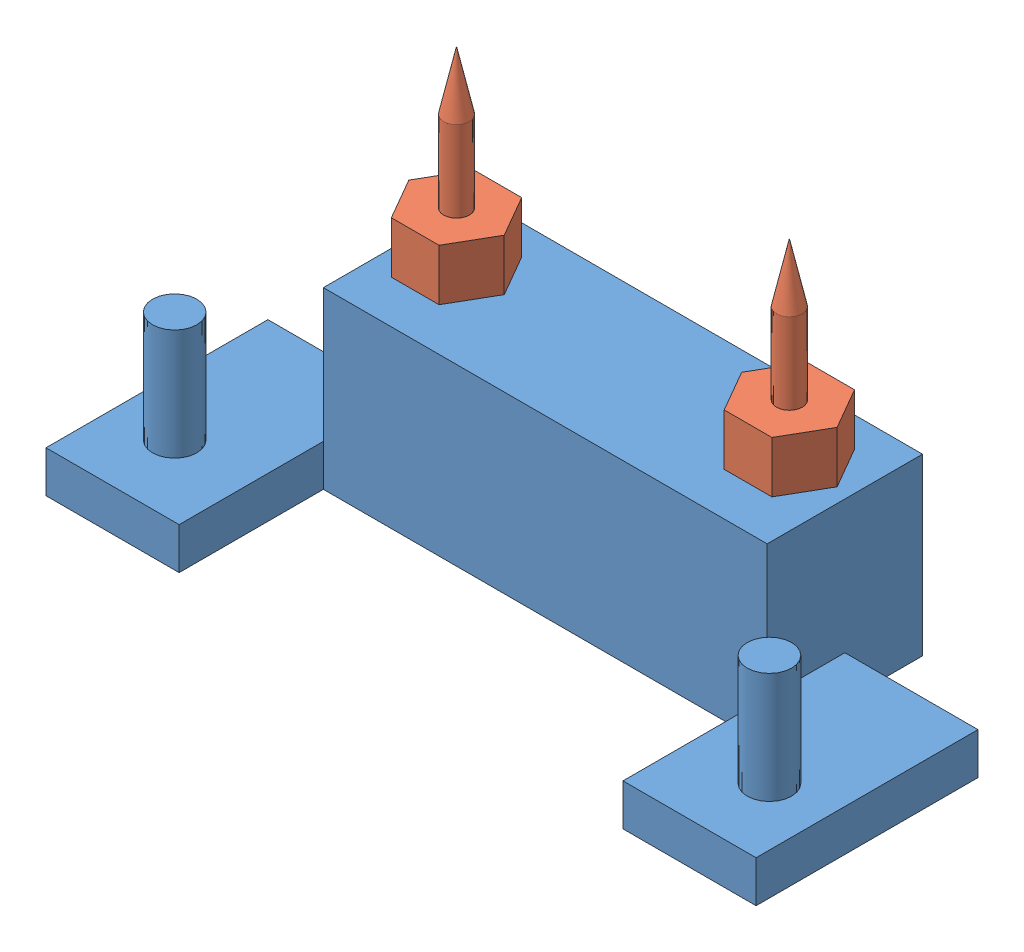
SolidWorks assembly Head_Assembly, configuration Default. Lengths in mm.
Overall size (40.64 21.33 17.14).
3 component instances, 2 part files, 4 mates.
Components (placement in the parent):
- Probe_Head-1: Probe_Head [Default] at origin size (40.64 10 17.14)
- Probe-1: Probe [Default] at (9.379 10.381 -0.7129) size (5.46 16.41 4.73)
- Probe-2: Probe [Default] at (-9.671 10.381 -0.7129) size (5.46 16.41 4.73)
Mates (geometry in assembly coordinates):
- Coincident1: coincident aligned: circle of Probe_Head-1; cylinder of Probe-1 through (9.379 4.92 -0.7129) axis (0 1 0) radius 1.0224
- Coincident3: coincident anti-aligned: plane of Probe_Head-1 through (9.379 4.92 -0.7129) normal (0 1 0); plane of Probe-1 through (9.379 4.92 -0.7129) normal (0 -1 0)
- Coincident4: coincident anti-aligned: plane of Probe_Head-1 through (-9.671 4.92 -0.7129) normal (0 1 0); plane of Probe-2 through (-9.671 4.92 -0.7129) normal (0 -1 0)
- Coincident5: coincident aligned: circle of Probe_Head-1; cylinder of Probe-2 through (-9.671 4.92 -0.7129) axis (0 1 0) radius 1.0224
